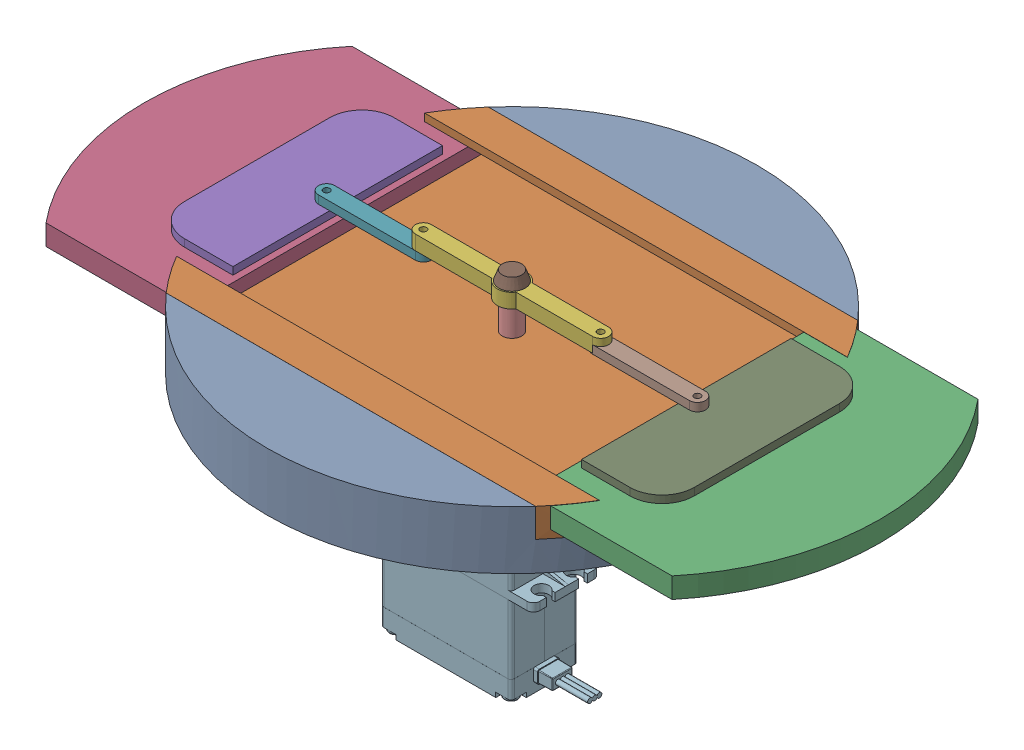
SolidWorks assembly AirBrakeAssem, configuration Default. Lengths in mm.
Overall size (228.28 107.25 152).
12 component instances, 9 part files, 26 mates.
Components (placement in the parent):
- BrakeBase-1: BrakeBase [Default] at (29.9957 38.205 72.1033) size (152 18 152)
- BrakeTray-1: BrakeTray [Default] at (29.9998 47.315 72.1215) size (152.03 8.9 99.9)
- BrakeFin-1: BrakeFin [Default] at (158.7601 56.165 72.1215) x (0 0 -1) z (-1 0 0) size (94.9 6.35 62.07)
- BrakeFin-2: BrakeFin [Default] at (-98.7604 47.5451 72.1215) x (0 0 -1) z (1 0 0) size (94.9 6.35 62.07)
- FinConnector-2: FinConnector [Default] at (-36.5546 53.8951 72.1215) x (0 0 -1) z (1 0 0) size (65 2.3 25)
- MainHinge-2: MainHinge [Default] at (29.9998 58.7351 72.1215) x (1 0 0.000599) z (-0.000599 0 1) size (60 4.5 9)
- ConnectingHinge-1: ConnectingHinge [Default] at (-12.5002 58.7351 72.1132) x (1 0 -0.000549) z (-0.000549 0 -1) size (35 2.54 5)
- ConnectingHinge-2: ConnectingHinge [Default] at (72.4998 58.465 72.1297) x (1 0 -0.000549) z (0.000549 0 1) size (35 2.54 5)
- FinConnector-3: FinConnector [Default] at (96.5543 56.165 72.1215) x (0 0 1) z (-1 0 0) size (65 2.3 25)
- MainShaft-2: MainShaft [Default] at (29.9998 63.2351 72.1215) x (0.008238 0 -0.999966) z (-0.999966 0 -0.008238) size (6 60 6)
- ShaftCap-1: ShaftCap [Default] at (29.9998 63.2351 72.1215) x (0.999242 0 0.038938) z (-0.038938 0 0.999242) size (8.18 3 8.18)
- ServoMotor-1: ServoMotor [Défaut] at (19.8148 -20.6649 72.1215) size (63.05 44.25 20.7)
Mates (geometry in assembly coordinates):
- Coincident1: coincident anti-aligned: plane of BrakeBase-1 through (-28.0123 47.315 22.1715) normal (0 0 1); plane of BrakeTray-1 through (-27.3002 56.215 22.1715) normal (0 0 -1)
- Coincident3: coincident anti-aligned: plane of BrakeBase-1 through (-28.0123 47.315 72.1033) normal (0 1 0); plane of BrakeTray-1 through (29.9998 47.315 72.1215) normal (0 -1 0)
- Coincident4: coincident anti-aligned: line of BrakeBase-1 through (-27.3002 47.315 22.1715) axis (0 1 0); line of BrakeTray-1 through (-27.3002 56.215 22.1715) axis (0 -1 0)
- Coincident5: coincident anti-aligned: line of BrakeTray-1 through (-29.3869 53.8951 24.6715) axis (1 0 0); line of BrakeFin-2 through (-22.0751 53.8951 24.6715) axis (-1 0 0)
- Coincident6: coincident aligned: line of BrakeTray-1 through (-29.3869 53.8951 119.5715) axis (1 0 0); line of BrakeFin-2 through (-67.0751 53.8951 119.5715) axis (1 0 0)
- Coincident7: coincident aligned: line of BrakeTray-1 through (-29.3869 49.815 24.6715) axis (1 0 0); line of BrakeFin-1 through (82.0748 49.815 24.6715) axis (1 0 0)
- Coincident8: coincident anti-aligned: line of BrakeTray-1 through (-29.3869 49.815 119.5715) axis (1 0 0); line of BrakeFin-1 through (127.0748 49.815 119.5715) axis (-1 0 0)
- Coincident13: coincident aligned: circle of BrakeFin-2; circle of FinConnector-2
- Parallel2: parallel aligned: line of BrakeFin-2 through (-22.0751 53.8951 119.5715) axis (0 0 -1); line of FinConnector-2 through (-24.0546 53.8951 104.6215) axis (0 0 -1)
- Concentric6: concentric anti-aligned: cylinder of MainHinge-2 through (2.4998 58.7351 72.105) axis (0 1 0) radius 1; cylinder of ConnectingHinge-1 through (2.4998 58.7351 72.105) axis (0 -1 0) radius 1
- Coincident24: coincident anti-aligned: plane of MainHinge-2 through (2.4998 58.7351 72.105) normal (0 -1 0); plane of ConnectingHinge-1 through (2.4998 58.7351 72.105) normal (0 1 0)
- Coincident25: coincident anti-aligned: plane of FinConnector-2 through (-36.5546 56.1951 72.1215) normal (0 1 0); plane of ConnectingHinge-1 through (2.4998 56.1951 72.105) normal (0 -1 0)
- Concentric7: concentric aligned: cylinder of FinConnector-2 through (-27.5002 56.1951 72.1215) axis (0 -1 0) radius 1; cylinder of ConnectingHinge-1 through (-27.5002 58.7351 72.1215) axis (0 -1 0) radius 1
- Parallel3: parallel anti-aligned: plane of BrakeTray-1 through (-46.0152 49.815 119.5715) normal (0 1 0); plane of MainHinge-2 through (2.4998 58.7351 72.105) normal (0 -1 0)
- Concentric8: concentric aligned: cylinder of BrakeTray-1 through (29.9998 47.315 72.1215) axis (0 1 0) radius 3; cylinder of MainHinge-2 through (29.9998 58.7351 72.1215) axis (0 1 0) radius 3
- Coincident27: coincident anti-aligned: circle of BrakeFin-1; circle of FinConnector-3
- Parallel4: parallel anti-aligned: line of BrakeFin-1 through (82.0748 56.165 119.5715) axis (0 0 -1); line of FinConnector-3 through (84.0543 56.165 39.6215) axis (0 0 1)
- Coincident30: coincident anti-aligned: plane of ConnectingHinge-2 through (87.4998 58.465 72.1215) normal (0 -1 0); plane of FinConnector-3 through (96.5543 58.465 72.1215) normal (0 1 0)
- Concentric9: concentric anti-aligned: cylinder of ConnectingHinge-2 through (87.4998 58.465 72.1215) axis (0 1 0) radius 1; cylinder of FinConnector-3 through (87.4998 58.465 72.1215) axis (0 -1 0) radius 1
- Concentric10: concentric aligned: cylinder of MainHinge-2 through (57.4998 58.7351 72.1379) axis (0 1 0) radius 1; cylinder of ConnectingHinge-2 through (57.4998 58.465 72.1379) axis (0 1 0) radius 1
- Concentric15: concentric aligned: cylinder of MainHinge-2 through (29.9998 58.7351 72.1215) axis (0 1 0) radius 3; cylinder of MainShaft-2 through (29.9998 3.2351 72.1215) axis (0 1 0) radius 3
- Concentric16: concentric anti-aligned: circle of MainShaft-2; circle of ShaftCap-1
- Coincident35: coincident anti-aligned: plane of MainShaft-2 through (29.9998 63.2351 72.1215) normal (0 1 0); plane of ShaftCap-1 through (29.9998 63.2351 72.1215) normal (0 -1 0)
- Coincident36: coincident anti-aligned: plane of MainHinge-2 through (2.4998 63.2351 72.105) normal (0 1 0); plane of ShaftCap-1 through (29.9998 63.2351 72.1215) normal (0 -1 0)
- Coincident37: coincident anti-aligned: plane of MainShaft-2 through (29.9998 3.2351 72.1215) normal (0 -1 0); plane of ServoMotor-1 through (19.8148 3.2351 72.1215) normal (0 1 0)
- Concentric17: concentric anti-aligned: circle of MainShaft-2; circle of ServoMotor-1
